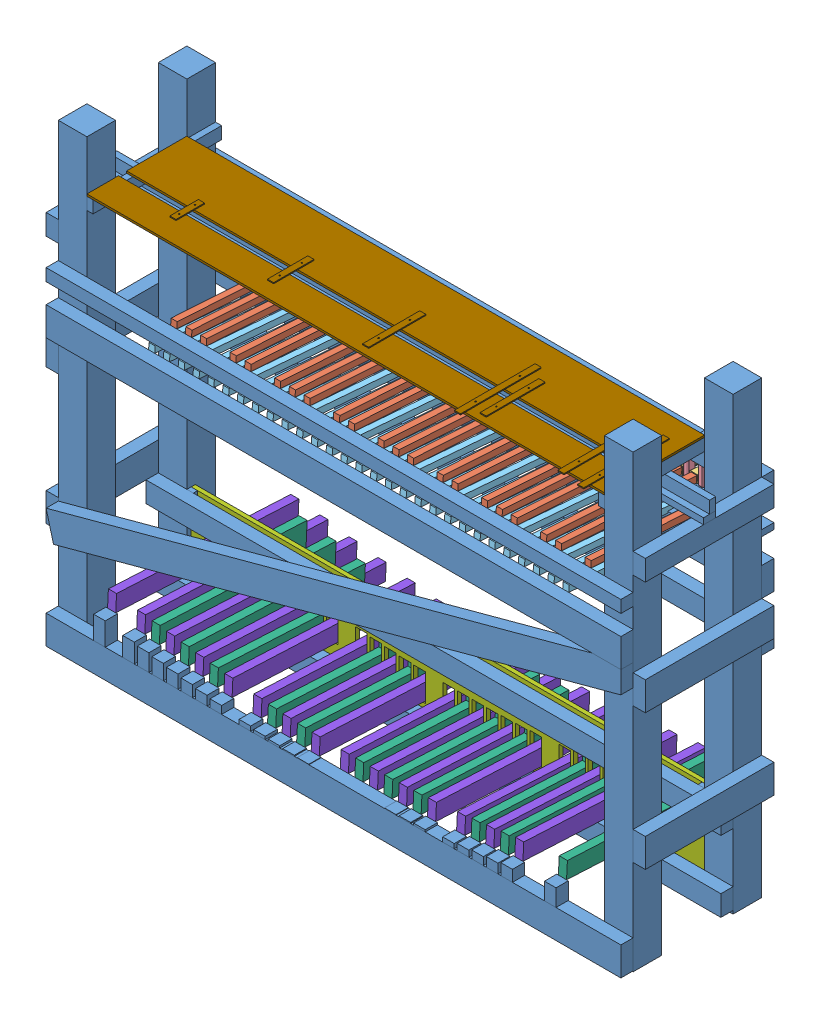
SolidWorks assembly Preliminary test assembly, configuration Default. Lengths in mm.
Overall size (1863.8 1400 655.19).
189 component instances, 9 part files, 73 mates.
Components (placement in the parent):
- diatonic keybase-1: diatonic keybase [Default] at (1614.7098 258.0879 1313.556) size (1863.8 1400 476)
- short key stick-1: short key stick [Default] at (1222.9097 1284.8964 1305.867) x (1 0 0) z (0 0.064242 0.997934) size (19 19 446)
- baton_alternate-1: baton_alternate [Default] at (1234.91 1295.674 1465.5037) x (0 -0.064242 -0.997934) z (1 0 0) size (123.41 25.7 25.7)
- baton spacer-1: baton spacer [Default] at (1253.9097 1273.0928 1313.556) x (-1 0 0) z (0 0 -1) size (16 107.5 22)
- baton spacer-2: baton spacer [Default] at (1207.9097 1273.0928 1313.556) x (-1 0 0) z (0 0 -1) size (16 107.5 22)
- baton spacer-3: baton spacer [Default] at (1184.9097 1176.5928 1313.556) x (-1 0 0) z (0 0 -1) size (16 107.5 22)
- baton spacer-4: baton spacer [Default] at (1138.9097 1176.5928 1313.556) x (-1 0 0) z (0 0 -1) size (16 107.5 22)
- baton spacer-5: baton spacer [Default] at (1092.9097 1176.5928 1313.556) x (-1 0 0) z (0 0 -1) size (16 107.5 22)
- baton spacer-6: baton spacer [Default] at (1046.9097 1176.5928 1313.556) x (-1 0 0) z (0 0 -1) size (16 107.5 22)
- baton spacer-7: baton spacer [Default] at (1000.9097 1176.5928 1313.556) x (-1 0 0) z (0 0 -1) size (16 107.5 22)
- baton spacer-8: baton spacer [Default] at (954.9097 1176.5928 1313.556) x (-1 0 0) z (0 0 -1) size (16 107.5 22)
- baton spacer-9: baton spacer [Default] at (908.9097 1176.5928 1313.556) x (-1 0 0) z (0 0 -1) size (16 107.5 22)
- baton spacer-10: baton spacer [Default] at (862.9097 1176.5928 1313.556) x (-1 0 0) z (0 0 -1) size (16 107.5 22)
- baton spacer-11: baton spacer [Default] at (816.9097 1176.5928 1313.556) x (-1 0 0) z (0 0 -1) size (16 107.5 22)
- baton spacer-12: baton spacer [Default] at (770.9097 1176.5928 1313.556) x (-1 0 0) z (0 0 -1) size (16 107.5 22)
- baton spacer-13: baton spacer [Default] at (724.9097 1176.5928 1313.556) x (-1 0 0) z (0 0 -1) size (16 107.5 22)
- baton spacer-14: baton spacer [Default] at (678.9097 1176.5928 1313.556) x (-1 0 0) z (0 0 -1) size (16 107.5 22)
- baton spacer-15: baton spacer [Default] at (632.9097 1176.5928 1313.556) x (-1 0 0) z (0 0 -1) size (16 107.5 22)
- baton spacer-16: baton spacer [Default] at (586.9097 1176.5928 1313.556) x (-1 0 0) z (0 0 -1) size (16 107.5 22)
- baton spacer-17: baton spacer [Default] at (540.9097 1176.5928 1313.556) x (-1 0 0) z (0 0 -1) size (16 107.5 22)
- baton spacer-18: baton spacer [Default] at (494.9097 1176.5928 1313.556) x (-1 0 0) z (0 0 -1) size (16 107.5 22)
- baton spacer-19: baton spacer [Default] at (448.9097 1176.5928 1313.556) x (-1 0 0) z (0 0 -1) size (16 107.5 22)
- baton spacer-20: baton spacer [Default] at (402.9097 1176.5928 1313.556) x (-1 0 0) z (0 0 -1) size (16 107.5 22)
- baton spacer-21: baton spacer [Default] at (356.9097 1176.5928 1313.556) x (-1 0 0) z (0 0 -1) size (16 107.5 22)
- baton spacer-22: baton spacer [Default] at (310.9097 1176.5928 1313.556) x (-1 0 0) z (0 0 -1) size (16 107.5 22)
- baton spacer-23: baton spacer [Default] at (264.9097 1176.5928 1313.556) x (-1 0 0) z (0 0 -1) size (16 107.5 22)
- baton spacer-24: baton spacer [Default] at (218.9097 1176.5928 1313.556) x (-1 0 0) z (0 0 -1) size (16 107.5 22)
- baton spacer-25: baton spacer [Default] at (172.9097 1176.5928 1313.556) x (-1 0 0) z (0 0 -1) size (16 107.5 22)
- baton spacer-26: baton spacer [Default] at (126.9097 1176.5928 1313.556) x (-1 0 0) z (0 0 -1) size (16 107.5 22)
- baton spacer-27: baton spacer [Default] at (80.9097 1176.5928 1313.556) x (-1 0 0) z (0 0 -1) size (16 107.5 22)
- baton spacer-28: baton spacer [Default] at (34.9097 1176.5928 1313.556) x (-1 0 0) z (0 0 -1) size (16 107.5 22)
- baton spacer-29: baton spacer [Default] at (-11.0903 1176.5928 1313.556) x (-1 0 0) z (0 0 -1) size (16 107.5 22)
- baton spacer-30: baton spacer [Default] at (-57.0903 1176.5928 1313.556) x (-1 0 0) z (0 0 -1) size (16 107.5 22)
- baton spacer-31: baton spacer [Default] at (-103.0903 1176.5928 1313.556) x (-1 0 0) z (0 0 -1) size (16 107.5 22)
- baton spacer-32: baton spacer [Default] at (-149.0903 1176.5928 1313.556) x (-1 0 0) z (0 0 -1) size (16 107.5 22)
- baton spacer-33: baton spacer [Default] at (1161.9097 1273.0928 1313.556) x (-1 0 0) z (0 0 -1) size (16 107.5 22)
- baton spacer-34: baton spacer [Default] at (1115.9097 1273.0928 1313.556) x (-1 0 0) z (0 0 -1) size (16 107.5 22)
- baton spacer-35: baton spacer [Default] at (1069.9097 1273.0928 1313.556) x (-1 0 0) z (0 0 -1) size (16 107.5 22)
- baton spacer-36: baton spacer [Default] at (1023.9097 1273.0928 1313.556) x (-1 0 0) z (0 0 -1) size (16 107.5 22)
- baton spacer-37: baton spacer [Default] at (977.9097 1273.0928 1313.556) x (-1 0 0) z (0 0 -1) size (16 107.5 22)
- baton spacer-38: baton spacer [Default] at (931.9097 1273.0928 1313.556) x (-1 0 0) z (0 0 -1) size (16 107.5 22)
- baton spacer-39: baton spacer [Default] at (885.9097 1273.0928 1313.556) x (-1 0 0) z (0 0 -1) size (16 107.5 22)
- baton spacer-40: baton spacer [Default] at (839.9097 1273.0928 1313.556) x (-1 0 0) z (0 0 -1) size (16 107.5 22)
- baton spacer-41: baton spacer [Default] at (793.9097 1273.0928 1313.556) x (-1 0 0) z (0 0 -1) size (16 107.5 22)
- baton spacer-42: baton spacer [Default] at (747.9097 1273.0928 1313.556) x (-1 0 0) z (0 0 -1) size (16 107.5 22)
- baton spacer-43: baton spacer [Default] at (701.9097 1273.0928 1313.556) x (-1 0 0) z (0 0 -1) size (16 107.5 22)
- baton spacer-44: baton spacer [Default] at (655.9097 1273.0928 1313.556) x (-1 0 0) z (0 0 -1) size (16 107.5 22)
- baton spacer-45: baton spacer [Default] at (609.9097 1273.0928 1313.556) x (-1 0 0) z (0 0 -1) size (16 107.5 22)
- baton spacer-46: baton spacer [Default] at (563.9097 1273.0928 1313.556) x (-1 0 0) z (0 0 -1) size (16 107.5 22)
- baton spacer-47: baton spacer [Default] at (517.9097 1273.0928 1313.556) x (-1 0 0) z (0 0 -1) size (16 107.5 22)
- baton spacer-48: baton spacer [Default] at (471.9097 1273.0928 1313.556) x (-1 0 0) z (0 0 -1) size (16 107.5 22)
- baton spacer-49: baton spacer [Default] at (425.9097 1273.0928 1313.556) x (-1 0 0) z (0 0 -1) size (16 107.5 22)
- baton spacer-50: baton spacer [Default] at (379.9097 1273.0928 1313.556) x (-1 0 0) z (0 0 -1) size (16 107.5 22)
- baton spacer-51: baton spacer [Default] at (333.9097 1273.0928 1313.556) x (-1 0 0) z (0 0 -1) size (16 107.5 22)
- baton spacer-52: baton spacer [Default] at (287.9097 1273.0928 1313.556) x (-1 0 0) z (0 0 -1) size (16 107.5 22)
- baton spacer-53: baton spacer [Default] at (241.9097 1273.0928 1313.556) x (-1 0 0) z (0 0 -1) size (16 107.5 22)
- baton spacer-54: baton spacer [Default] at (195.9097 1273.0928 1313.556) x (-1 0 0) z (0 0 -1) size (16 107.5 22)
- baton spacer-55: baton spacer [Default] at (149.9097 1273.0928 1313.556) x (-1 0 0) z (0 0 -1) size (16 107.5 22)
- baton spacer-56: baton spacer [Default] at (103.9097 1273.0928 1313.556) x (-1 0 0) z (0 0 -1) size (16 107.5 22)
- baton spacer-57: baton spacer [Default] at (57.9097 1273.0928 1313.556) x (-1 0 0) z (0 0 -1) size (16 107.5 22)
- baton spacer-58: baton spacer [Default] at (11.9097 1273.0928 1313.556) x (-1 0 0) z (0 0 -1) size (16 107.5 22)
- baton spacer-59: baton spacer [Default] at (-34.0903 1273.0928 1313.556) x (-1 0 0) z (0 0 -1) size (16 107.5 22)
- baton spacer-60: baton spacer [Default] at (-80.0903 1273.0928 1313.556) x (-1 0 0) z (0 0 -1) size (16 107.5 22)
- baton_alternate-12: baton_alternate [Default] at (1142.91 1295.674 1465.5037) x (0 -0.064242 -0.997934) z (1 0 0) size (123.41 25.7 25.7)
- baton_alternate-13: baton_alternate [Default] at (1096.91 1295.674 1465.5037) x (0 -0.064242 -0.997934) z (1 0 0) size (123.41 25.7 25.7)
- baton_alternate-15: baton_alternate [Default] at (1004.91 1295.674 1465.5037) x (0 -0.064242 -0.997934) z (1 0 0) size (123.41 25.7 25.7)
- baton_alternate-16: baton_alternate [Default] at (958.91 1295.674 1465.5037) x (0 -0.064242 -0.997934) z (1 0 0) size (123.41 25.7 25.7)
- baton_alternate-17: baton_alternate [Default] at (912.91 1295.674 1465.5037) x (0 -0.064242 -0.997934) z (1 0 0) size (123.41 25.7 25.7)
- baton_alternate-19: baton_alternate [Default] at (820.91 1295.674 1465.5037) x (0 -0.064242 -0.997934) z (1 0 0) size (123.41 25.7 25.7)
- baton_alternate-20: baton_alternate [Default] at (774.91 1295.674 1465.5037) x (0 -0.064242 -0.997934) z (1 0 0) size (123.41 25.7 25.7)
- baton_alternate-22: baton_alternate [Default] at (682.91 1295.674 1465.5037) x (0 -0.064242 -0.997934) z (1 0 0) size (123.41 25.7 25.7)
- baton_alternate-23: baton_alternate [Default] at (636.91 1295.674 1465.5037) x (0 -0.064242 -0.997934) z (1 0 0) size (123.41 25.7 25.7)
- baton_alternate-24: baton_alternate [Default] at (590.91 1295.674 1465.5037) x (0 -0.064242 -0.997934) z (1 0 0) size (123.41 25.7 25.7)
- baton_alternate-26: baton_alternate [Default] at (498.91 1295.674 1465.5037) x (0 -0.064242 -0.997934) z (1 0 0) size (123.41 25.7 25.7)
- baton_alternate-27: baton_alternate [Default] at (452.91 1295.674 1465.5037) x (0 -0.064242 -0.997934) z (1 0 0) size (123.41 25.7 25.7)
- baton_alternate-29: baton_alternate [Default] at (360.91 1295.674 1465.5037) x (0 -0.064242 -0.997934) z (1 0 0) size (123.41 25.7 25.7)
- baton_alternate-30: baton_alternate [Default] at (314.91 1295.674 1465.5037) x (0 -0.064242 -0.997934) z (1 0 0) size (123.41 25.7 25.7)
- baton_alternate-31: baton_alternate [Default] at (268.91 1295.674 1465.5037) x (0 -0.064242 -0.997934) z (1 0 0) size (123.41 25.7 25.7)
- baton_alternate-33: baton_alternate [Default] at (176.91 1295.674 1465.5037) x (0 -0.064242 -0.997934) z (1 0 0) size (123.41 25.7 25.7)
- baton_alternate-34: baton_alternate [Default] at (130.91 1295.674 1465.5037) x (0 -0.064242 -0.997934) z (1 0 0) size (123.41 25.7 25.7)
- baton_alternate-36: baton_alternate [Default] at (38.91 1295.674 1465.5037) x (0 -0.064242 -0.997934) z (1 0 0) size (123.41 25.7 25.7)
- baton_alternate-37: baton_alternate [Default] at (-7.09 1295.674 1465.5037) x (0 -0.064242 -0.997934) z (1 0 0) size (123.41 25.7 25.7)
- baton_alternate-38: baton_alternate [Default] at (-53.09 1295.674 1465.5037) x (0 -0.064242 -0.997934) z (1 0 0) size (123.41 25.7 25.7)
- short key stick-12: short key stick [Default] at (1130.9097 1284.8964 1305.867) x (1 0 0) z (0 0.064242 0.997934) size (19 19 446)
- short key stick-13: short key stick [Default] at (1084.9097 1284.8964 1305.867) x (1 0 0) z (0 0.064242 0.997934) size (19 19 446)
- short key stick-15: short key stick [Default] at (992.9097 1284.8964 1305.867) x (1 0 0) z (0 0.064242 0.997934) size (19 19 446)
- short key stick-16: short key stick [Default] at (946.9097 1284.8964 1305.867) x (1 0 0) z (0 0.064242 0.997934) size (19 19 446)
- short key stick-17: short key stick [Default] at (900.9097 1284.8964 1305.867) x (1 0 0) z (0 0.064242 0.997934) size (19 19 446)
- short key stick-19: short key stick [Default] at (808.9097 1284.8964 1305.867) x (1 0 0) z (0 0.064242 0.997934) size (19 19 446)
- short key stick-20: short key stick [Default] at (762.9097 1284.8964 1305.867) x (1 0 0) z (0 0.064242 0.997934) size (19 19 446)
- short key stick-22: short key stick [Default] at (670.9097 1284.8964 1305.867) x (1 0 0) z (0 0.064242 0.997934) size (19 19 446)
- short key stick-23: short key stick [Default] at (624.9097 1284.8964 1305.867) x (1 0 0) z (0 0.064242 0.997934) size (19 19 446)
- short key stick-24: short key stick [Default] at (578.9097 1284.8964 1305.867) x (1 0 0) z (0 0.064242 0.997934) size (19 19 446)
- short key stick-26: short key stick [Default] at (486.9097 1284.8964 1305.867) x (1 0 0) z (0 0.064242 0.997934) size (19 19 446)
- short key stick-27: short key stick [Default] at (440.9097 1284.8964 1305.867) x (1 0 0) z (0 0.064242 0.997934) size (19 19 446)
- short key stick-29: short key stick [Default] at (348.9097 1284.8964 1305.867) x (1 0 0) z (0 0.064242 0.997934) size (19 19 446)
- short key stick-30: short key stick [Default] at (302.9097 1284.8964 1305.867) x (1 0 0) z (0 0.064242 0.997934) size (19 19 446)
- short key stick-31: short key stick [Default] at (256.9097 1284.8964 1305.867) x (1 0 0) z (0 0.064242 0.997934) size (19 19 446)
- short key stick-33: short key stick [Default] at (164.9097 1284.8964 1305.867) x (1 0 0) z (0 0.064242 0.997934) size (19 19 446)
- short key stick-34: short key stick [Default] at (118.9097 1284.8964 1305.867) x (1 0 0) z (0 0.064242 0.997934) size (19 19 446)
- short key stick-36: short key stick [Default] at (26.9097 1284.8964 1305.867) x (1 0 0) z (0 0.064242 0.997934) size (19 19 446)
- short key stick-37: short key stick [Default] at (-19.0903 1284.8964 1305.867) x (1 0 0) z (0 0.064242 0.997934) size (19 19 446)
- short key stick-38: short key stick [Default] at (-65.0903 1284.8964 1305.867) x (1 0 0) z (0 0.064242 0.997934) size (19 19 446)
- long key stick-1: long key stick [Default] at (1154.2843 1171.5159 1233.4907) x (1 0 0) z (0 0.080965 0.996717) size (19 19 519)
- baton_alternate-39: baton_alternate [Default] at (1141.784 1184.4702 1392.9648) x (0 -0.080965 -0.996717) z (-1 0 0) size (123.41 25.7 25.7)
- long key stick-2: long key stick [Default] at (1108.2843 1171.5159 1233.4907) x (1 0 0) z (0 0.080965 0.996717) size (19 19 519)
- long key stick-3: long key stick [Default] at (1062.2843 1171.5159 1233.4907) x (1 0 0) z (0 0.080965 0.996717) size (19 19 519)
- long key stick-4: long key stick [Default] at (1016.2843 1171.5159 1233.4907) x (1 0 0) z (0 0.080965 0.996717) size (19 19 519)
- long key stick-5: long key stick [Default] at (970.2843 1171.5159 1233.4907) x (1 0 0) z (0 0.080965 0.996717) size (19 19 519)
- long key stick-6: long key stick [Default] at (924.2843 1171.5159 1233.4907) x (1 0 0) z (0 0.080965 0.996717) size (19 19 519)
- long key stick-7: long key stick [Default] at (878.2843 1171.5159 1233.4907) x (1 0 0) z (0 0.080965 0.996717) size (19 19 519)
- long key stick-8: long key stick [Default] at (832.2843 1171.5159 1233.4907) x (1 0 0) z (0 0.080965 0.996717) size (19 19 519)
- long key stick-9: long key stick [Default] at (786.2843 1171.5159 1233.4907) x (1 0 0) z (0 0.080965 0.996717) size (19 19 519)
- long key stick-10: long key stick [Default] at (740.2843 1171.5159 1233.4907) x (1 0 0) z (0 0.080965 0.996717) size (19 19 519)
- long key stick-11: long key stick [Default] at (694.2843 1171.5159 1233.4907) x (1 0 0) z (0 0.080965 0.996717) size (19 19 519)
- long key stick-12: long key stick [Default] at (648.2843 1171.5159 1233.4907) x (1 0 0) z (0 0.080965 0.996717) size (19 19 519)
- long key stick-13: long key stick [Default] at (602.2843 1171.5159 1233.4907) x (1 0 0) z (0 0.080965 0.996717) size (19 19 519)
- long key stick-14: long key stick [Default] at (556.2843 1171.5159 1233.4907) x (1 0 0) z (0 0.080965 0.996717) size (19 19 519)
- long key stick-15: long key stick [Default] at (510.2843 1171.5159 1233.4907) x (1 0 0) z (0 0.080965 0.996717) size (19 19 519)
- long key stick-16: long key stick [Default] at (464.2843 1171.5159 1233.4907) x (1 0 0) z (0 0.080965 0.996717) size (19 19 519)
- long key stick-17: long key stick [Default] at (418.2843 1171.5159 1233.4907) x (1 0 0) z (0 0.080965 0.996717) size (19 19 519)
- long key stick-18: long key stick [Default] at (372.2843 1171.5159 1233.4907) x (1 0 0) z (0 0.080965 0.996717) size (19 19 519)
- long key stick-19: long key stick [Default] at (326.2843 1171.5159 1233.4907) x (1 0 0) z (0 0.080965 0.996717) size (19 19 519)
- long key stick-20: long key stick [Default] at (280.2843 1171.5159 1233.4907) x (1 0 0) z (0 0.080965 0.996717) size (19 19 519)
- long key stick-21: long key stick [Default] at (234.2843 1171.5159 1233.4907) x (1 0 0) z (0 0.080965 0.996717) size (19 19 519)
- long key stick-22: long key stick [Default] at (188.2843 1171.5159 1233.4907) x (1 0 0) z (0 0.080965 0.996717) size (19 19 519)
- long key stick-23: long key stick [Default] at (142.2843 1171.5159 1233.4907) x (1 0 0) z (0 0.080965 0.996717) size (19 19 519)
- long key stick-24: long key stick [Default] at (96.2843 1171.5159 1233.4907) x (1 0 0) z (0 0.080965 0.996717) size (19 19 519)
- long key stick-25: long key stick [Default] at (50.2843 1171.5159 1233.4907) x (1 0 0) z (0 0.080965 0.996717) size (19 19 519)
- long key stick-26: long key stick [Default] at (4.2843 1171.5159 1233.4907) x (1 0 0) z (0 0.080965 0.996717) size (19 19 519)
- long key stick-27: long key stick [Default] at (-41.7157 1171.5159 1233.4907) x (1 0 0) z (0 0.080965 0.996717) size (19 19 519)
- long key stick-28: long key stick [Default] at (-87.7157 1171.5159 1233.4907) x (1 0 0) z (0 0.080965 0.996717) size (19 19 519)
- long key stick-29: long key stick [Default] at (-133.7157 1171.5159 1233.4907) x (1 0 0) z (0 0.080965 0.996717) size (19 19 519)
- baton_alternate-40: baton_alternate [Default] at (1095.784 1184.4702 1392.9648) x (0 -0.080965 -0.996717) z (-1 0 0) size (123.41 25.7 25.7)
- baton_alternate-41: baton_alternate [Default] at (1049.784 1184.4702 1392.9648) x (0 -0.080965 -0.996717) z (-1 0 0) size (123.41 25.7 25.7)
- baton_alternate-42: baton_alternate [Default] at (1003.784 1184.4702 1392.9648) x (0 -0.080965 -0.996717) z (-1 0 0) size (123.41 25.7 25.7)
- baton_alternate-43: baton_alternate [Default] at (957.784 1184.4702 1392.9648) x (0 -0.080965 -0.996717) z (-1 0 0) size (123.41 25.7 25.7)
- baton_alternate-44: baton_alternate [Default] at (911.784 1184.4702 1392.9648) x (0 -0.080965 -0.996717) z (-1 0 0) size (123.41 25.7 25.7)
- baton_alternate-45: baton_alternate [Default] at (865.784 1184.4702 1392.9648) x (0 -0.080965 -0.996717) z (-1 0 0) size (123.41 25.7 25.7)
- baton_alternate-46: baton_alternate [Default] at (819.784 1184.4702 1392.9648) x (0 -0.080965 -0.996717) z (-1 0 0) size (123.41 25.7 25.7)
- baton_alternate-47: baton_alternate [Default] at (773.784 1184.4702 1392.9648) x (0 -0.080965 -0.996717) z (-1 0 0) size (123.41 25.7 25.7)
- baton_alternate-48: baton_alternate [Default] at (727.784 1184.4702 1392.9648) x (0 -0.080965 -0.996717) z (-1 0 0) size (123.41 25.7 25.7)
- baton_alternate-49: baton_alternate [Default] at (681.784 1184.4702 1392.9648) x (0 -0.080965 -0.996717) z (-1 0 0) size (123.41 25.7 25.7)
- baton_alternate-50: baton_alternate [Default] at (635.784 1184.4702 1392.9648) x (0 -0.080965 -0.996717) z (-1 0 0) size (123.41 25.7 25.7)
- baton_alternate-51: baton_alternate [Default] at (589.784 1184.4702 1392.9648) x (0 -0.080965 -0.996717) z (-1 0 0) size (123.41 25.7 25.7)
- baton_alternate-52: baton_alternate [Default] at (543.784 1184.4702 1392.9648) x (0 -0.080965 -0.996717) z (-1 0 0) size (123.41 25.7 25.7)
- baton_alternate-53: baton_alternate [Default] at (497.784 1184.4702 1392.9648) x (0 -0.080965 -0.996717) z (-1 0 0) size (123.41 25.7 25.7)
- baton_alternate-54: baton_alternate [Default] at (451.784 1184.4702 1392.9648) x (0 -0.080965 -0.996717) z (-1 0 0) size (123.41 25.7 25.7)
- baton_alternate-55: baton_alternate [Default] at (405.784 1184.4702 1392.9648) x (0 -0.080965 -0.996717) z (-1 0 0) size (123.41 25.7 25.7)
- baton_alternate-56: baton_alternate [Default] at (359.784 1184.4702 1392.9648) x (0 -0.080965 -0.996717) z (-1 0 0) size (123.41 25.7 25.7)
- baton_alternate-57: baton_alternate [Default] at (313.784 1184.4702 1392.9648) x (0 -0.080965 -0.996717) z (-1 0 0) size (123.41 25.7 25.7)
- baton_alternate-58: baton_alternate [Default] at (267.784 1184.4702 1392.9648) x (0 -0.080965 -0.996717) z (-1 0 0) size (123.41 25.7 25.7)
- baton_alternate-59: baton_alternate [Default] at (221.784 1184.4702 1392.9648) x (0 -0.080965 -0.996717) z (-1 0 0) size (123.41 25.7 25.7)
- baton_alternate-60: baton_alternate [Default] at (175.784 1184.4702 1392.9648) x (0 -0.080965 -0.996717) z (-1 0 0) size (123.41 25.7 25.7)
- baton_alternate-61: baton_alternate [Default] at (129.784 1184.4702 1392.9648) x (0 -0.080965 -0.996717) z (-1 0 0) size (123.41 25.7 25.7)
- baton_alternate-62: baton_alternate [Default] at (83.784 1184.4702 1392.9648) x (0 -0.080965 -0.996717) z (-1 0 0) size (123.41 25.7 25.7)
- baton_alternate-63: baton_alternate [Default] at (37.784 1184.4702 1392.9648) x (0 -0.080965 -0.996717) z (-1 0 0) size (123.41 25.7 25.7)
- baton_alternate-64: baton_alternate [Default] at (-8.216 1184.4702 1392.9648) x (0 -0.080965 -0.996717) z (-1 0 0) size (123.41 25.7 25.7)
- baton_alternate-65: baton_alternate [Default] at (-54.216 1184.4702 1392.9648) x (0 -0.080965 -0.996717) z (-1 0 0) size (123.41 25.7 25.7)
- baton_alternate-66: baton_alternate [Default] at (-100.216 1184.4702 1392.9648) x (0 -0.080965 -0.996717) z (-1 0 0) size (123.41 25.7 25.7)
- baton_alternate-67: baton_alternate [Default] at (-146.216 1184.4702 1392.9648) x (0 -0.080965 -0.996717) z (-1 0 0) size (123.41 25.7 25.7)
- short pedal-1: short pedal [Default] at (1144.1343 451.7422 1750.2457) x (-1 0 0) z (0 -0.051586 -0.998669) size (25.4 127 454)
- pedal keybase-2: pedal keybase [Default] at (1312.9088 258.0843 1427.256) x (-1 0.000003 0) z (0 0 -1) size (1609.8 284.68 12.7)
- long pedal-1: long pedal [Default] at (1008.4433 405.2151 1182.9972) x (0 0.050227 0.998738) z (-1 0 0) size (568 50.8 25.4)
- short pedal-2: short pedal [Default] at (963.2111 427.7423 1750.2473) x (-1 0 0) z (0 -0.051525 -0.998672) size (25.4 127 454)
- short pedal-3: short pedal [Default] at (872.7532 417.7469 1750.3387) x (-1 0 0) z (0 -0.047927 -0.998851) size (25.4 127 454)
- long pedal-2: long pedal [Default] at (917.9826 394.4916 1182.9957) x (0 0.049741 0.998762) z (-1 0 0) size (568 50.8 25.4)
- long pedal-3: long pedal [Default] at (827.5235 412.7424 1750.2484) x (0 -0.051479 -0.998674) z (1 0 0) size (568 50.8 25.4)
- long pedal-4: long pedal [Default] at (737.0606 377.6561 1182.991) x (0 0.047696 0.998862) z (-1 0 0) size (568 50.8 25.4)
- short pedal-4: short pedal [Default] at (691.8288 401.7471 1750.3425) x (-1 0 0) z (0 -0.047777 -0.998858) size (25.4 127 454)
- long pedal-5: long pedal [Default] at (646.5996 374.6938 1182.9884) x (0 0.044994 0.998987) z (-1 0 0) size (568 50.8 25.4)
- short pedal-5: short pedal [Default] at (601.3677 398.7479 1750.3598) x (-1 0 0) z (0 -0.047094 -0.99889) size (25.4 127 454)
- short pedal-14: short pedal [Default] at (510.9677 398.7481 1750.3598) x (-1 0 0) z (0 -0.047094 -0.99889) size (25.4 127 454)
- long pedal-7: long pedal [Default] at (556.1349 370.7516 1182.9944) x (0 0.049284 0.998785) z (-1 0 0) size (568 50.8 25.4)
- long pedal-8: long pedal [Default] at (465.7349 370.7519 1182.9944) x (0 0.049284 0.998785) z (-1 0 0) size (568 50.8 25.4)
- long pedal-9: long pedal [Default] at (375.2149 372.6104 1182.9929) x (0 0.048654 0.998816) z (-1 0 0) size (568 50.8 25.4)
- short pedal-15: short pedal [Default] at (329.9857 401.7423 1750.2471) x (-1 0 0) z (0 -0.05153 -0.998671) size (25.4 127 454)
- long pedal-10: long pedal [Default] at (284.754 378.2128 1182.9896) x (0 0.046717 0.998908) z (-1 0 0) size (568 50.8 25.4)
- short pedal-16: short pedal [Default] at (239.5258 407.7438 1750.276) x (-1 0 0) z (0 -0.050394 -0.998729) size (25.4 127 454)
- long pedal-11: long pedal [Default] at (194.2911 412.7467 1750.3355) x (0 -0.04805 -0.998845) z (1 0 0) size (568 50.8 25.4)
- long pedal-12: long pedal [Default] at (103.8319 395.889 1182.9903) x (0 0.047286 0.998881) z (-1 0 0) size (568 50.8 25.4)
- short pedal-17: short pedal [Default] at (58.6035 427.7426 1750.252) x (-1 0 0) z (0 -0.051338 -0.998681) size (25.4 127 454)
- long pedal-13: long pedal [Default] at (13.3712 406.1989 1182.9925) x (0 0.048499 0.998823) z (-1 0 0) size (568 50.8 25.4)
- short pedal-18: short pedal [Default] at (-31.8587 439.7508 1750.4236) x (-1 0 0) z (0 -0.044583 -0.999006) size (25.4 127 454)
- long pedal-14: long pedal [Default] at (-77.0911 417.0339 1182.9982) x (0 0.050545 0.998722) z (-1 0 0) size (568 50.8 25.4)
- short pedal-19: short pedal [Default] at (-122.3197 451.7475 1750.3524) x (-1 0 0) z (0 -0.047387 -0.998877) size (25.4 127 454)
- long pedal-15: long pedal [Default] at (-167.5496 430.7042 1182.9908) x (0 0.047611 0.998866) z (-1 0 0) size (568 50.8 25.4)
- long pedal-16: long pedal [Default] at (-258.1103 440.5629 1183.0012) x (0 0.051373 0.99868) z (-1 0 0) size (568 50.8 25.4)
- tone bar mockup_version 3-1: tone bar mockup_version 3 [Default] at (1186.4347 1531.1178 1818.0563) x (-1 0 0) z (0 0 1) size (1610.17 9.53 332.99)
Mates (geometry in assembly coordinates):
- Coincident2: coincident: line of baton_alternate-1 through (1232.4097 1295.3747 1305.1924) axis (0 -0.997934 0.064242); line of short key stick-1 through (1232.4097 1275.416 1306.4773) axis (0 0.997934 -0.064242)
- Coincident3: coincident: line of short key stick-1 through (1213.4097 1275.416 1306.4773) axis (1 0 0); line of baton_alternate-1 through (1232.4097 1275.416 1306.4773) axis (-1 0 0)
- Parallel1: parallel: plane of diatonic keybase-1 through (1401.8097 258.0879 1313.556) normal (1 0 0); plane of short key stick-1 through (1213.4097 1304.0678 1751.556) normal (-1 0 0)
- Coincident13: coincident: line of diatonic keybase-1 through (-423.9903 1304.0678 1751.556) axis (1 0 0); line of short key stick-1 through (1213.4097 1304.0678 1751.556) axis (1 0 0)
- Coincident14: coincident: plane of diatonic keybase-1 through (1312.9096 1273.0928 1351.556) normal (0 1 0); point of baton_alternate-1
- Coincident15: coincident: plane of diatonic keybase-1 through (1312.9096 258.0879 1313.556) normal (0 0 -1); plane of baton spacer-1 through (1253.9097 1273.0928 1313.556) normal (0 0 1)
- Coincident16: coincident: plane of diatonic keybase-1 through (1312.9096 258.0879 1313.556) normal (0 0 -1); plane of baton spacer-1 through (1253.9097 1273.0928 1313.556) normal (0 0 1)
- Coincident17: coincident: plane of diatonic keybase-1 through (1312.9096 1350.5928 1351.556) normal (0 -1 0); plane of baton spacer-1 through (1253.9097 1350.5928 1332.556) normal (0 1 0)
- Coincident18: coincident: line of diatonic keybase-1 through (1237.9097 1276.5928 1313.556) axis (0 1 0); plane of baton spacer-1 through (1237.9097 1350.5928 1332.556) normal (-1 0 0)
- Coincident19: coincident: plane of diatonic keybase-1 through (1312.9096 258.0879 1313.556) normal (0 0 -1); plane of baton spacer-2 through (1207.9097 1273.0928 1313.556) normal (0 0 1)
- Coincident20: coincident: plane of diatonic keybase-1 through (1312.9096 258.0879 1313.556) normal (0 0 -1); plane of baton spacer-2 through (1207.9097 1273.0928 1313.556) normal (0 0 1)
- Coincident21: coincident: plane of diatonic keybase-1 through (1312.9096 1350.5928 1351.556) normal (0 -1 0); plane of baton spacer-2 through (1207.9097 1350.5928 1332.556) normal (0 1 0)
- Coincident22: coincident: line of diatonic keybase-1 through (1207.9097 1350.5928 1313.556) axis (0 -1 0); plane of baton spacer-2 through (1207.9097 1273.0928 1332.556) normal (1 0 0)
- Coincident23: coincident: plane of diatonic keybase-1 through (1312.9096 258.0879 1313.556) normal (0 0 -1); plane of baton spacer-3 through (1184.9097 1176.5928 1313.556) normal (0 0 1)
- Coincident24: coincident: plane of diatonic keybase-1 through (1312.9096 258.0879 1313.556) normal (0 0 -1); plane of baton spacer-3 through (1184.9097 1176.5928 1313.556) normal (0 0 1)
- Coincident25: coincident: line of diatonic keybase-1 through (1168.9097 1176.5928 1313.556) axis (0 1 0); plane of baton spacer-3 through (1168.9097 1254.0928 1332.556) normal (-1 0 0)
- Coincident26: coincident: plane of diatonic keybase-1 through (1312.9096 1254.0928 1351.556) normal (0 -1 0); plane of baton spacer-3 through (1184.9097 1254.0928 1332.556) normal (0 1 0)
- ProfileCenter1: profile center: plane of long key stick-1 through (1154.2843 1171.5159 1233.4907) normal (0 -0.080965 -0.996717); plane of baton_alternate-39 through (1141.784 1171.5159 1233.4907) normal (0 0.080965 0.996717)
- Coincident32: coincident: line of diatonic keybase-1 through (-423.9903 1204.0678 1751.556) axis (1 0 0); line of long key stick-1 through (1144.7843 1204.0678 1751.556) axis (1 0 0)
- Coincident33: coincident: line of diatonic keybase-1 through (1126.1343 426.3761 1751.556) axis (1 0 0); line of short pedal-1 through (1156.8343 426.3761 1751.556) axis (-1 0 0)
- Coincident34: coincident: moEndPointRef_w of diatonic keybase-1; moEndPointRef_w of short pedal-1
- Coincident36: coincident: point of diatonic keybase-1; point of pedal keybase-2
- Coincident38: coincident: point of diatonic keybase-1; point of pedal keybase-2
- Coincident40: coincident: plane of diatonic keybase-1 through (1614.7098 258.0879 1427.256) normal (0 0 -1); plane of pedal keybase-2 through (1312.9088 258.0843 1427.256) normal (0 0 1)
- Coincident41: coincident: line of diatonic keybase-1 through (990.4433 408.3761 1751.556) axis (1 0 0); line of long pedal-1 through (995.7433 408.3761 1751.556) axis (1 0 0)
- Coincident42: coincident: moEndPointRef_w of diatonic keybase-1; moEndPointRef_w of long pedal-1
- Coincident43: coincident: line of diatonic keybase-1 through (945.2111 402.3761 1751.556) axis (1 0 0); line of short pedal-2 through (975.9111 402.3761 1751.556) axis (-1 0 0)
- Coincident44: coincident: moEndPointRef_w of diatonic keybase-1; moEndPointRef_w of short pedal-2
- Coincident45: coincident: line of diatonic keybase-1 through (854.7532 392.3761 1751.556) axis (1 0 0); line of short pedal-3 through (885.4532 392.3761 1751.556) axis (-1 0 0)
- Coincident47: coincident: moEndPointRef_w of diatonic keybase-1; moEndPointRef_w of short pedal-3
- Coincident48: coincident: line of diatonic keybase-1 through (899.9826 397.3761 1751.556) axis (1 0 0); line of long pedal-2 through (905.2826 397.3761 1751.556) axis (1 0 0)
- Coincident49: coincident: moEndPointRef_w of diatonic keybase-1; moEndPointRef_w of long pedal-2
- Coincident54: coincident: line of diatonic keybase-1 through (809.5235 387.3761 1751.556) axis (1 0 0); line of long pedal-3 through (840.2235 387.3761 1751.556) axis (-1 0 0)
- Coincident55: coincident: moEndPointRef_w of diatonic keybase-1; moEndPointRef_w of long pedal-3
- Coincident56: coincident: line of diatonic keybase-1 through (719.0606 379.3761 1751.556) axis (1 0 0); line of long pedal-4 through (724.3606 379.3761 1751.556) axis (1 0 0)
- Coincident57: coincident: moEndPointRef_w of diatonic keybase-1; moEndPointRef_w of long pedal-4
- Coincident58: coincident: line of diatonic keybase-1 through (673.8288 376.3761 1751.556) axis (1 0 0); line of short pedal-4 through (704.5288 376.3761 1751.556) axis (-1 0 0)
- Coincident59: coincident: moEndPointRef_w of diatonic keybase-1; moEndPointRef_w of short pedal-4
- Coincident60: coincident: line of diatonic keybase-1 through (628.5996 374.8761 1751.556) axis (1 0 0); line of long pedal-5 through (633.8996 374.8761 1751.556) axis (1 0 0)
- Coincident63: coincident: moEndPointRef_w of diatonic keybase-1; moEndPointRef_w of long pedal-5
- Coincident64: coincident: line of diatonic keybase-1 through (-423.9903 373.3761 1751.556) axis (1 0 0); line of short pedal-5 through (614.0677 373.3761 1751.556) axis (-1 0 0)
- Coincident65: coincident: moEndPointRef_w of short pedal-5; point of assembly
- Coincident66: coincident: line of diatonic keybase-1 through (-423.9903 373.3761 1751.556) axis (1 0 0); line of long pedal-7 through (543.4349 373.3761 1751.556) axis (1 0 0)
- Coincident68: coincident: moEndPointRef_w of long pedal-7; point of assembly
- Coincident69: coincident: line of diatonic keybase-1 through (357.2149 374.8761 1751.556) axis (1 0 0); line of long pedal-9 through (362.5149 374.8761 1751.556) axis (1 0 0)
- Coincident70: coincident: moEndPointRef_w of diatonic keybase-1; moEndPointRef_w of long pedal-9
- Coincident71: coincident: line of diatonic keybase-1 through (311.9857 376.3761 1751.556) axis (1 0 0); line of short pedal-15 through (342.6857 376.3761 1751.556) axis (-1 0 0)
- Coincident72: coincident: moEndPointRef_w of diatonic keybase-1; moEndPointRef_w of short pedal-15
- Coincident73: coincident: line of diatonic keybase-1 through (266.754 379.3761 1751.556) axis (1 0 0); line of long pedal-10 through (272.054 379.3761 1751.556) axis (1 0 0)
- Coincident74: coincident: moEndPointRef_w of diatonic keybase-1; moEndPointRef_w of long pedal-10
- Coincident75: coincident: line of diatonic keybase-1 through (221.5258 382.3761 1751.556) axis (1 0 0); line of short pedal-16 through (252.2258 382.3761 1751.556) axis (-1 0 0)
- Coincident76: coincident: moEndPointRef_w of diatonic keybase-1; moEndPointRef_w of short pedal-16
- Coincident77: coincident: line of diatonic keybase-1 through (176.2911 387.3761 1751.556) axis (1 0 0); line of long pedal-11 through (206.9911 387.3761 1751.556) axis (-1 0 0)
- Coincident78: coincident: moEndPointRef_w of diatonic keybase-1; moEndPointRef_w of long pedal-11
- Coincident79: coincident: line of diatonic keybase-1 through (85.8319 397.3761 1751.556) axis (1 0 0); line of long pedal-12 through (91.1319 397.3761 1751.556) axis (1 0 0)
- Coincident80: coincident: moEndPointRef_w of diatonic keybase-1; moEndPointRef_w of long pedal-12
- Coincident81: coincident: line of diatonic keybase-1 through (40.6035 402.3761 1751.556) axis (1 0 0); line of short pedal-17 through (71.3035 402.3761 1751.556) axis (-1 0 0)
- Coincident82: coincident: moEndPointRef_w of diatonic keybase-1; moEndPointRef_w of short pedal-17
- Coincident83: coincident: line of diatonic keybase-1 through (-4.6288 408.3761 1751.556) axis (1 0 0); line of long pedal-13 through (0.6712 408.3761 1751.556) axis (1 0 0)
- Coincident84: coincident: moEndPointRef_w of diatonic keybase-1; moEndPointRef_w of long pedal-13
- Coincident85: coincident: line of diatonic keybase-1 through (-49.8587 414.3761 1751.556) axis (1 0 0); line of short pedal-18 through (-19.1587 414.3761 1751.556) axis (-1 0 0)
- Coincident86: coincident: moEndPointRef_w of diatonic keybase-1; moEndPointRef_w of short pedal-18
- Coincident87: coincident: line of diatonic keybase-1 through (-95.0911 420.3761 1751.556) axis (1 0 0); line of long pedal-14 through (-89.7911 420.3761 1751.556) axis (1 0 0)
- Coincident88: coincident: moEndPointRef_w of diatonic keybase-1; moEndPointRef_w of long pedal-14
- Coincident89: coincident: line of diatonic keybase-1 through (-140.3197 426.3761 1751.556) axis (1 0 0); line of short pedal-19 through (-109.6197 426.3761 1751.556) axis (-1 0 0)
- Coincident90: coincident: moEndPointRef_w of diatonic keybase-1; moEndPointRef_w of short pedal-19
- Coincident91: coincident: line of diatonic keybase-1 through (-185.5496 432.3761 1751.556) axis (1 0 0); line of long pedal-15 through (-180.2496 432.3761 1751.556) axis (1 0 0)
- Coincident92: coincident: moEndPointRef_w of diatonic keybase-1; moEndPointRef_w of long pedal-15
- Coincident93: coincident: line of diatonic keybase-1 through (-276.1103 444.3761 1751.556) axis (1 0 0); line of long pedal-16 through (-270.8103 444.3761 1751.556) axis (1 0 0)
- Coincident94: coincident: moEndPointRef_w of diatonic keybase-1; moEndPointRef_w of long pedal-16
- Coincident95: coincident: plane of diatonic keybase-1 through (1274.8097 281.9373 1662.556) normal (-1 0 0); plane of tone bar mockup_version 3-1 through (1274.8097 1521.5928 1818.0563) normal (1 0 0)
- Coincident96: coincident: plane of diatonic keybase-1 through (1255.8097 1521.5928 1440.556) normal (0 1 0); plane of tone bar mockup_version 3-1 through (1186.4347 1521.5928 1818.0563) normal (0 -1 0)
- Coincident98: coincident: plane of diatonic keybase-1 through (1312.9096 258.0879 1440.556) normal (0 0 1); plane of tone bar mockup_version 3-1 through (1186.4347 1521.5928 1440.556) normal (0 0 -1)
